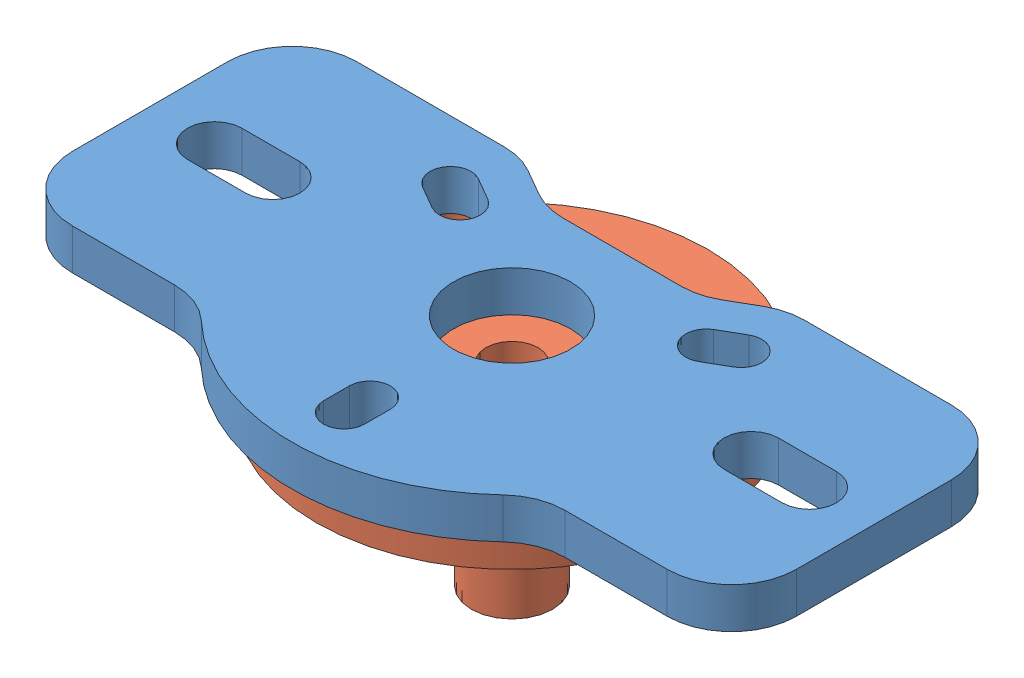
SolidWorks assembly NeedleMountAssembly, configuration Default. Lengths in mm.
Overall size (71.12 23 40.84).
2 component instances, 2 part files, 3 mates.
Components (placement in the parent):
- NeedleMountTop-1: NeedleMountTop [Default] at origin size (71.12 4 35.56)
- NeedleMountBottom-1: NeedleMountBottom [Default] at origin size (38.5 19 38.5)
Mates (geometry in assembly coordinates):
- Coincident1: coincident anti-aligned: plane of NeedleMountTop-1 through (14.7222 0 -7.62) normal (0 -1 0); plane of NeedleMountBottom-1 through (0 0 0) normal (0 1 0)
- Coincident2: coincident aligned: circle of NeedleMountTop-1; circle of NeedleMountBottom-1
- Coincident3: coincident aligned: circle of NeedleMountTop-1; circle of NeedleMountBottom-1
